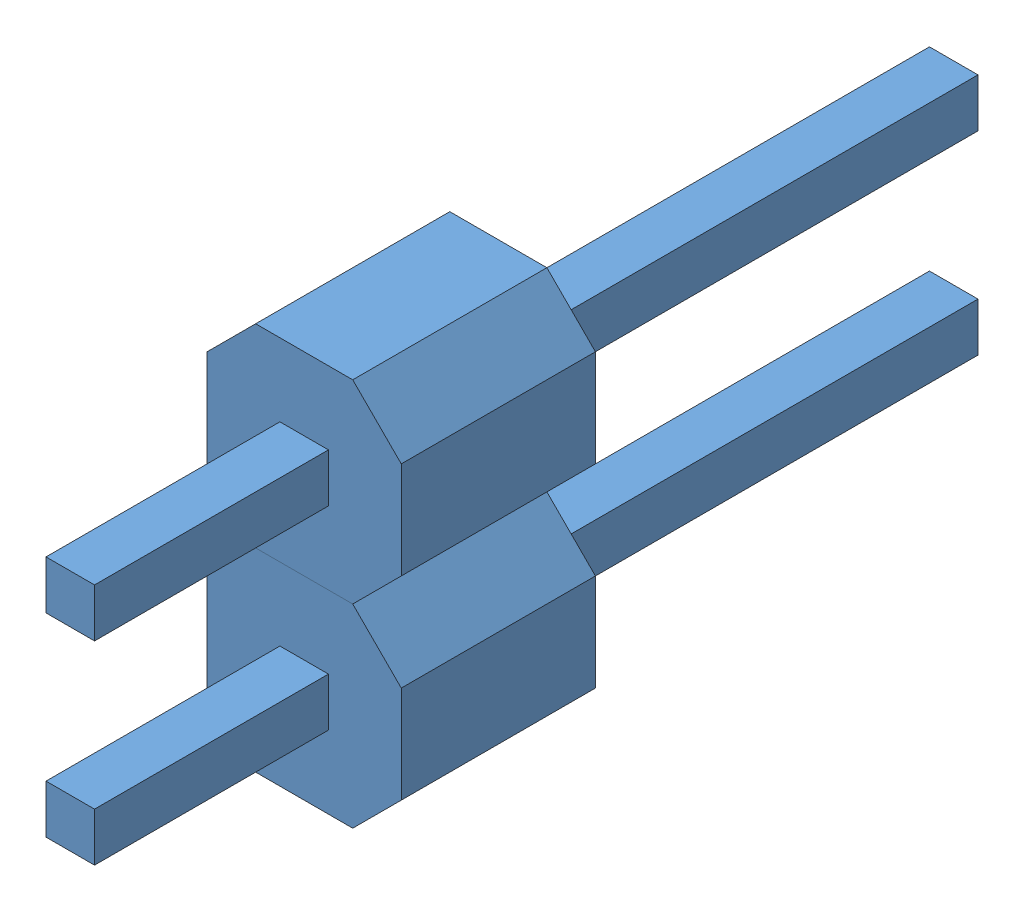
SolidWorks assembly Header 2 Pin, configuration Default. Lengths in mm.
Overall size (2.54 5.08 11.56).
2 component instances, 1 part files, 0 mates.
Components (placement in the parent):
- Header Pin-1: Header Pin [Default] at (-60.0026 20.0311 14.1279) size (2.54 2.54 11.56)
- Header Pin-3: Header Pin [Default] at (-60.0026 22.5711 14.1279) size (2.54 2.54 11.56)
